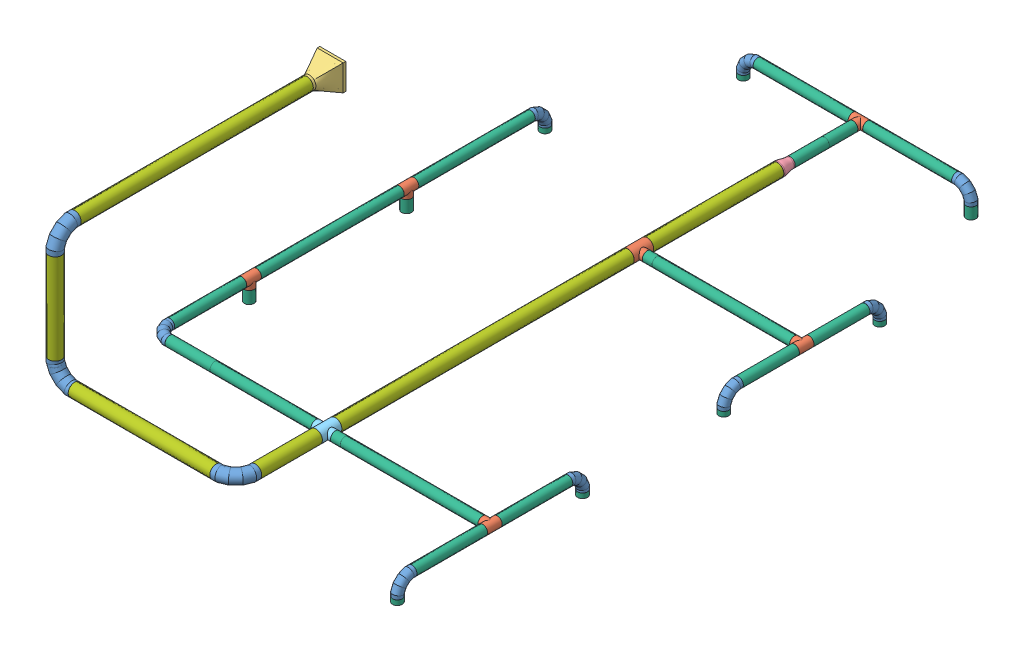
SolidWorks assembly HVAC Ducting10-HVAC Round System, configuration Default. Lengths in mm.
Overall size (28079.33 12943.59 49335.66).
52 component instances, 7 part files, 16 mates.
Components (placement in the parent):
- hvac round duct 90deg elbow-1: hvac round duct 90deg elbow [Round Duct 90Deg Elbow 0.75DIA x 1.13R] at (12650 9875 -975) x (0 -1 0) z (-1 0 0) size (1510 1510 750)
- hvac round duct 90deg elbow-3: hvac round duct 90deg elbow [Round Duct 90Deg Elbow 0.75DIA x 1.13R] at (12650 9875 -10725) x (0 -1 0) z (1 0 0) size (1510 1510 750)
- hvac round duct 90deg elbow-6: hvac round duct 90deg elbow [Round Duct 90Deg Elbow 0.75DIA x 1.13R] at (12650 9875 12150) x (0 -1 0) z (1 0 0) size (1510 1510 750)
- hvac round duct 90deg elbow-8: hvac round duct 90deg elbow [Round Duct 90Deg Elbow 0.75DIA x 1.13R] at (12650 9875 24150) x (0 -1 0) z (-1 0 0) size (1510 1510 750)
- hvac round duct tee-1: hvac round duct tee [Round Duct Tee 0.75 x 0.75 x 0.75] at (-13114.7749 11000 -1197.8664) x (0 0 1) z (1 0 0) size (1145 947.5 750)
- hvac round duct 90deg elbow-13: hvac round duct 90deg elbow [Round Duct 90Deg Elbow 0.75DIA x 1.13R] at (-13114.7749 9875 -10725) x (0 -1 0) z (1 0 0) size (1510 1510 750)
- hvac round duct 90deg elbow-15: hvac round duct 90deg elbow [Round Duct 90Deg Elbow 0.75DIA x 1.13R] at (-7875 9875 -23000) x (0 -1 0) z (0 0 -1) size (1510 1510 750)
- hvac round duct tee-5: hvac round duct tee [Round Duct Tee 0.75 x 0.75 x 0.75] at (0 11000 -23000) x (1 0 0) z (0 -1 0) size (1145 947.5 750)
- hvac round duct tee-7: hvac round duct tee [Round Duct Tee 0.75 x 0.75 x 0.75] at (12650 11000 -5850) x (0 0 -1) z (0 1 0) size (1145 947.5 750)
- hvac round duct tee-8: hvac round duct tee [Round Duct Tee 0.75 x 0.75 x 0.75] at (12650 11000 18150) x (0 0 -1) z (0 1 0) size (1145 947.5 750)
- hvac round duct tee-12: hvac round duct tee [Round Duct Tee 0.75 x 0.75 x 0.75] at (-13114.7749 11000 10919.1216) x (0 0 -1) z (-1 0 0) size (1145 947.5 750)
- hvac round duct 90deg elbow-16: hvac round duct 90deg elbow [Round Duct 90Deg Elbow 0.75DIA x 1.13R] at (7406.5004 9875 -23000) x (0 -1 0) z (0 0 1) size (1510 1510 750)
- hvac square-round-1: hvac square-round [Square_Round 2.00x2.00 to 1.00 DIA] at (-13899 20946 3700) x (0 0 1) z (-1 0 0) size (2020 2000 2000)
- hvac round duct 90deg elbow-17: hvac round duct 90deg elbow [Round Duct 90Deg Elbow 1.00DIA x 1.50R] at (-13899 19446 23567.2282) x (0 -1 0) z (-1 0 0) size (2010 2010 1000)
- hvac round duct 90deg elbow-18: hvac round duct 90deg elbow [Round Duct 90Deg Elbow 1.00DIA x 1.50R] at (-12399 12500 25067.2282) x (1 0 0) z (0 0 -1) size (2010 2010 1000)
- hvac round duct 90deg elbow-19: hvac round duct 90deg elbow [Round Duct 90Deg Elbow 1.00DIA x 1.50R] at (-1500 11000 23567.2282) x (0 0 -1) z (0 -1 0) size (2010 2010 1000)
- hvac round reducer-2: hvac round reducer [Round Duct Reducer 1.00 x 0.75] at (0 11000 -16618.6901) x (0 0 -1) z (1 0 0) size (1020 1000 1000)
- hvac round duct cross-1: hvac round duct cross [Round Duct Cross 1.00 x 1.00 x 0.75 x 0.75] at (0 11000 18150) x (0 0 1) z (0 1 0) size (1520 1520 1000)
- hvac round duct tee-13: hvac round duct tee [Round Duct Tee 1.00 x 1.00 x 0.75] at (0 11000 -5850) x (0 0 1) z (0 1 0) size (1520 1260 1000)
- hvac round duct 90deg elbow-20: hvac round duct 90deg elbow [Round Duct 90Deg Elbow 0.75DIA x 1.13R] at (-11989.7749 11000 17025) x (0 0 -1) z (0 1 0) size (1510 1510 750)
- RoundDuct075mDIA2mmThick^HVAC Ducting10-HVAC Round System-1: RoundDuct075mDIA2mmThick^HVAC Ducting10-HVAC Round System [Round Duct 0.75m DIA,2mm Thick, 2] at (12650 11000 -5287.5) x (0.707107 0.707107 0) z (0 0 1) size (750 750 4312.5) (virtual)
- RoundDuct075mDIA2mmThick^HVAC Ducting10-HVAC Round System-2: RoundDuct075mDIA2mmThick^HVAC Ducting10-HVAC Round System [Round Duct 0.75m DIA,2mm Thick, 3] at (12650 9875 150) x (0.707107 0 0.707107) z (0 -1 0) size (750 750 375) (virtual)
- RoundDuct075mDIA2mmThick^HVAC Ducting10-HVAC Round System-3: RoundDuct075mDIA2mmThick^HVAC Ducting10-HVAC Round System [Round Duct 0.75m DIA,2mm Thick, 2] at (12650 11000 -6412.5) x (0.707107 0.707107 0) z (0 0 -1) size (750 750 4312.5) (virtual)
- RoundDuct075mDIA2mmThick^HVAC Ducting10-HVAC Round System-4: RoundDuct075mDIA2mmThick^HVAC Ducting10-HVAC Round System [Round Duct 0.75m DIA,2mm Thick, 3] at (12650 9875 -11850) x (0.707107 0 0.707107) z (0 -1 0) size (750 750 375) (virtual)
- RoundDuct075mDIA2mmThick^HVAC Ducting10-HVAC Round System-5: RoundDuct075mDIA2mmThick^HVAC Ducting10-HVAC Round System [Round Duct 0.75m DIA,2mm Thick] at (12650 11000 18712.5) x (0.707107 0.707107 0) z (0 0 1) size (750 750 5437.5) (virtual)
- RoundDuct075mDIA2mmThick^HVAC Ducting10-HVAC Round System-6: RoundDuct075mDIA2mmThick^HVAC Ducting10-HVAC Round System [Round Duct 0.75m DIA,2mm Thick] at (12650 11000 17587.5) x (0.707107 0.707107 0) z (0 0 -1) size (750 750 5437.5) (virtual)
- RoundDuct075mDIA2mmThick^HVAC Ducting10-HVAC Round System-9: RoundDuct075mDIA2mmThick^HVAC Ducting10-HVAC Round System [Round Duct 0.75m DIA,2mm Thick, 3] at (12650 9875 11025) x (0.707107 0 0.707107) z (0 -1 0) size (750 750 375) (virtual)
- RoundDuct075mDIA2mmThick^HVAC Ducting10-HVAC Round System-12: RoundDuct075mDIA2mmThick^HVAC Ducting10-HVAC Round System [Round Duct 0.75m DIA,2mm Thick, 3] at (12650 9875 25275) x (0.707107 0 0.707107) z (0 -1 0) size (750 750 375) (virtual)
- RoundDuct075mDIA2mmThick^HVAC Ducting10-HVAC Round System-14: RoundDuct075mDIA2mmThick^HVAC Ducting10-HVAC Round System [Round Duct 0.75m DIA,2mm Thick, 4] at (-13114.7749 11000 -1760.3664) x (0.707107 0.707107 0) z (0 0 -1) size (750 750 8964.63) (virtual)
- RoundDuct075mDIA2mmThick^HVAC Ducting10-HVAC Round System-15: RoundDuct075mDIA2mmThick^HVAC Ducting10-HVAC Round System [Round Duct 0.75m DIA,2mm Thick, 5] at (-13114.7749 10437.5 -1197.8664) x (0.707107 0 0.707107) z (0 -1 0) size (750 750 937.5) (virtual)
- RoundDuct075mDIA2mmThick^HVAC Ducting10-HVAC Round System-22: RoundDuct075mDIA2mmThick^HVAC Ducting10-HVAC Round System [Round Duct 0.75m DIA,2mm Thick, 3] at (-13114.7749 9875 -11850) x (0.707107 0 0.707107) z (0 -1 0) size (750 750 375) (virtual)
- RoundDuct075mDIA2mmThick^HVAC Ducting10-HVAC Round System-27: RoundDuct075mDIA2mmThick^HVAC Ducting10-HVAC Round System [Round Duct 0.75m DIA,2mm Thick, 8] at (-562.5 11000 -23000) x (0 0.707107 0.707107) z (-1 0 0) size (750 750 7312.5) (virtual)
- RoundDuct075mDIA2mmThick^HVAC Ducting10-HVAC Round System-29: RoundDuct075mDIA2mmThick^HVAC Ducting10-HVAC Round System [Round Duct 0.75m DIA,2mm Thick, 3] at (-9000 9875 -23000) x (0.707107 0 0.707107) z (0 -1 0) size (750 750 375) (virtual)
- RoundDuct075mDIA2mmThick^HVAC Ducting10-HVAC Round System-34: RoundDuct075mDIA2mmThick^HVAC Ducting10-HVAC Round System [Round Duct 0.75m DIA,2mm Thick, 1] at (-13114.7749 11000 -635.3664) x (0.707107 0.707107 0) z (0 0 1) size (750 750 10991.99) (virtual)
- RoundDuct075mDIA2mmThick^HVAC Ducting10-HVAC Round System-38: RoundDuct075mDIA2mmThick^HVAC Ducting10-HVAC Round System [Round Duct 0.75m DIA,2mm Thick, 11] at (-13114.7749 11000 11481.6216) x (0.707107 0.707107 0) z (0 0 1) size (750 750 5543.38) (virtual)
- RoundDuct075mDIA2mmThick^HVAC Ducting10-HVAC Round System-40: RoundDuct075mDIA2mmThick^HVAC Ducting10-HVAC Round System [Round Duct 0.75m DIA,2mm Thick, 5] at (-13114.7749 10437.5 10919.1216) x (0.707107 0 0.707107) z (0 -1 0) size (750 750 937.5) (virtual)
- RoundDuct075mDIA2mmThick^HVAC Ducting10-HVAC Round System-41: RoundDuct075mDIA2mmThick^HVAC Ducting10-HVAC Round System [Round Duct 0.75m DIA,2mm Thick, 12] at (0 11000 -22437.5) x (0.707107 0.707107 0) z (0 0 1) size (750 750 2187.58) (virtual)
- RoundDuct075mDIA2mmThick^HVAC Ducting10-HVAC Round System-45: RoundDuct075mDIA2mmThick^HVAC Ducting10-HVAC Round System [Round Duct 0.75m DIA,2mm Thick, 9] at (562.5 11000 -23000) x (0 0.707107 0.707107) z (1 0 0) size (750 750 6844) (virtual)
- RoundDuct075mDIA2mmThick^HVAC Ducting10-HVAC Round System-46: RoundDuct075mDIA2mmThick^HVAC Ducting10-HVAC Round System [Round Duct 0.75m DIA,2mm Thick, 10] at (8531.5004 9875 -23000) x (0.707107 0 0.707107) z (0 -1 0) size (750 750 872.59) (virtual)
- RoundDuct100mDIA2mmThick^HVAC Ducting10-HVAC Round System-1: RoundDuct100mDIA2mmThick^HVAC Ducting10-HVAC Round System [Round Duct 1.00m DIA,2mm Thick] at (-13899 20946 5700) x (0.707107 0.707107 0) z (0 0 1) size (1000 1000 17867.23) (virtual)
- RoundDuct100mDIA2mmThick^HVAC Ducting10-HVAC Round System-2: RoundDuct100mDIA2mmThick^HVAC Ducting10-HVAC Round System [Round Duct 1.00m DIA,2mm Thick, 1] at (-13899 19446 25067.2282) x (0.707107 0 0.707107) z (0 -1 0) size (1000 1000 6946) (virtual)
- RoundDuct100mDIA2mmThick^HVAC Ducting10-HVAC Round System-3: RoundDuct100mDIA2mmThick^HVAC Ducting10-HVAC Round System [Round Duct 1.00m DIA,2mm Thick, 2] at (-12399 11000 25067.2282) x (0 0.707107 0.707107) z (1 0 0) size (1000 1000 10899) (virtual)
- RoundDuct100mDIA2mmThick^HVAC Ducting10-HVAC Round System-4: RoundDuct100mDIA2mmThick^HVAC Ducting10-HVAC Round System [Round Duct 1.00m DIA,2mm Thick, 4] at (0 11000 23567.2282) x (0.707107 0.707107 0) z (0 0 -1) size (1000 1000 4667.23) (virtual)
- RoundDuct075mDIA2mmThick^HVAC Ducting10-HVAC Round System-47: RoundDuct075mDIA2mmThick^HVAC Ducting10-HVAC Round System [Round Duct 0.75m DIA,2mm Thick, 13] at (0 11000 -17618.6901) x (0.707107 0.707107 0) z (0 0 -1) size (750 750 2631.23) (virtual)
- RoundDuct100mDIA2mmThick^HVAC Ducting10-HVAC Round System-5: RoundDuct100mDIA2mmThick^HVAC Ducting10-HVAC Round System [Round Duct 1.00m DIA,2mm Thick, 5] at (0 11000 17400) x (0.707107 0.707107 0) z (0 0 -1) size (1000 1000 22500) (virtual)
- RoundDuct075mDIA2mmThick^HVAC Ducting10-HVAC Round System-48: RoundDuct075mDIA2mmThick^HVAC Ducting10-HVAC Round System [Round Duct 0.75m DIA,2mm Thick, 14] at (-750 11000 18150) x (0 0.707107 0.707107) z (-1 0 0) size (750 750 7770.76) (virtual)
- RoundDuct075mDIA2mmThick^HVAC Ducting10-HVAC Round System-49: RoundDuct075mDIA2mmThick^HVAC Ducting10-HVAC Round System [Round Duct 0.75m DIA,2mm Thick, 7] at (750 11000 18150) x (0 0.707107 0.707107) z (1 0 0) size (750 750 750) (virtual)
- RoundDuct075mDIA2mmThick^HVAC Ducting10-HVAC Round System-50: RoundDuct075mDIA2mmThick^HVAC Ducting10-HVAC Round System [Round Duct 0.75m DIA,2mm Thick, 15] at (12087.5 11000 18150) x (0 0.707107 0.707107) z (-1 0 0) size (750 750 10587.5) (virtual)
- RoundDuct075mDIA2mmThick^HVAC Ducting10-HVAC Round System-51: RoundDuct075mDIA2mmThick^HVAC Ducting10-HVAC Round System [Round Duct 0.75m DIA,2mm Thick, 16] at (-11989.7749 11000 18150) x (0 0.707107 0.707107) z (1 0 0) size (750 750 3469.02) (virtual)
- RoundDuct075mDIA2mmThick^HVAC Ducting10-HVAC Round System-52: RoundDuct075mDIA2mmThick^HVAC Ducting10-HVAC Round System [Round Duct 0.75m DIA,2mm Thick, 15] at (12087.5 11000 -5850) x (0 0.707107 0.707107) z (-1 0 0) size (750 750 10587.5) (virtual)
- RoundDuct100mDIA2mmThick^HVAC Ducting10-HVAC Round System-6: RoundDuct100mDIA2mmThick^HVAC Ducting10-HVAC Round System [Round Duct 1.00m DIA,2mm Thick, 6] at (0 11000 -6600) x (0.707107 0.707107 0) z (0 0 -1) size (1000 1000 10018.69) (virtual)
- RoundDuct075mDIA2mmThick^HVAC Ducting10-HVAC Round System-53: RoundDuct075mDIA2mmThick^HVAC Ducting10-HVAC Round System [Round Duct 0.75m DIA,2mm Thick, 7] at (750 11000 -5850) x (0 0.707107 0.707107) z (1 0 0) size (750 750 750) (virtual)
Mates (geometry in assembly coordinates):
- Symmetric11: symmetric aligned: plane of hvac round duct tee-5 through (0 11000 -23000) normal (0 0 1); plane of Part-1 through (-17500 10000 -28300) normal (0 0 -1); plane of Part-1 through (-7800 0 -17700) normal (0 0 1)
- Symmetric12: symmetric aligned: plane of hvac round duct tee-5 through (0 11000 -23000) normal (1 0 0); plane of Part-1 through (-17500 10000 -28000) normal (1 0 0); plane of Part-1 through (17500 10000 -28000) normal (-1 0 0)
- Distance6: distance = 1000 mm anti-aligned: plane of hvac round duct tee-5 through (0 11000 -23000) normal (0 -1 0); plane of Part-1 through (0 10000 0) normal (0 1 0)
- Coincident1: coincident anti-aligned: plane of Part1^HVAC Round System-1 through (-15500 22147 3700) normal (0 0 1); plane of hvac round duct end-1 through (-13250 21447 3700) normal (0 0 -1)
- Symmetric2: symmetric aligned: plane of hvac round duct end-1 through (-13250 21447 3700) normal (1 0 0); plane of Part1^HVAC Round System-1 through (-12300 22147 -12300) normal (1 0 0); plane of Part1^HVAC Round System-1 through (-15500 22147 -12300) normal (-1 0 0)
- Parallel1: parallel aligned: plane of Part1^HVAC Round System-1 through (0 22147 0) normal (0 1 0); plane of hvac round duct end-1 through (-13250 21447 3700) normal (0 1 0)
- Distance1: distance = 1700 mm aligned: plane of hvac round duct end-1 through (-13250 21447 3700) normal (0 1 0); plane of Part1^HVAC Round System-1 through (0 22147 0) normal (0 1 0)
- Symmetric5: symmetric aligned: plane of hvac round duct tee-7 through (12650 11000 -5850) normal (0 0 -1); plane of Part-1 through (7500 10000 -5700) normal (0 0 1); plane of Part-1 through (7500 10000 -6000) normal (0 0 -1)
- Distance3: distance = 1000 mm aligned: plane of hvac round duct tee-7 through (12650 11000 -5850) normal (0 1 0); plane of Part-1 through (0 10000 0) normal (0 1 0)
- Symmetric6: symmetric aligned: plane of hvac round duct tee-7 through (12650 11000 -5850) normal (-1 0 0); plane of Part-1 through (17800 10000 -28000) normal (1 0 0); plane of Part-1 through (7500 10000 18300) normal (-1 0 0)
- Symmetric7: symmetric aligned: plane of hvac round duct tee-8 through (12650 11000 18150) normal (0 0 -1); plane of Part-1 through (7500 10000 18300) normal (0 0 1); plane of Part-1 through (7500 10000 18000) normal (0 0 -1)
- Distance4: distance = 1000 mm aligned: plane of hvac round duct tee-8 through (12650 11000 18150) normal (0 1 0); plane of Part-1 through (0 10000 0) normal (0 1 0)
- Symmetric8: symmetric aligned: plane of hvac round duct tee-8 through (12650 11000 18150) normal (-1 0 0); plane of Part-1 through (17800 10000 -28000) normal (1 0 0); plane of Part-1 through (7500 10000 18300) normal (-1 0 0)
- Coincident21: coincident anti-aligned: plane of hvac square-round-1 through (-13899 20946 3700) normal (0 0 -1); plane of Part1^HVAC Round System-1 through (-15500 22147 3700) normal (0 0 1)
- Width1: width anti-aligned: plane of Part1^HVAC Round System-1 through (-12300 22147 -12300) normal (1 0 0); plane of hvac square-round-1 through (-15500 22147 -12300) normal (-1 0 0); plane of Part1^HVAC Round System-1 through (-14899 21946 3900) normal (-1 0 0); plane of hvac square-round-1 through (-12901 21946 3900) normal (-1 0 0)
- Width2: width aligned: plane of Part1^HVAC Round System-1 through (0 22147 0) normal (0 1 0); plane of hvac square-round-1 through (0 19747 0) normal (0 1 0); plane of Part-1 through (-14899 21946 3900) normal (0 1 0); plane of hvac square-round-1 through (-14899 19948 3900) normal (0 1 0)
